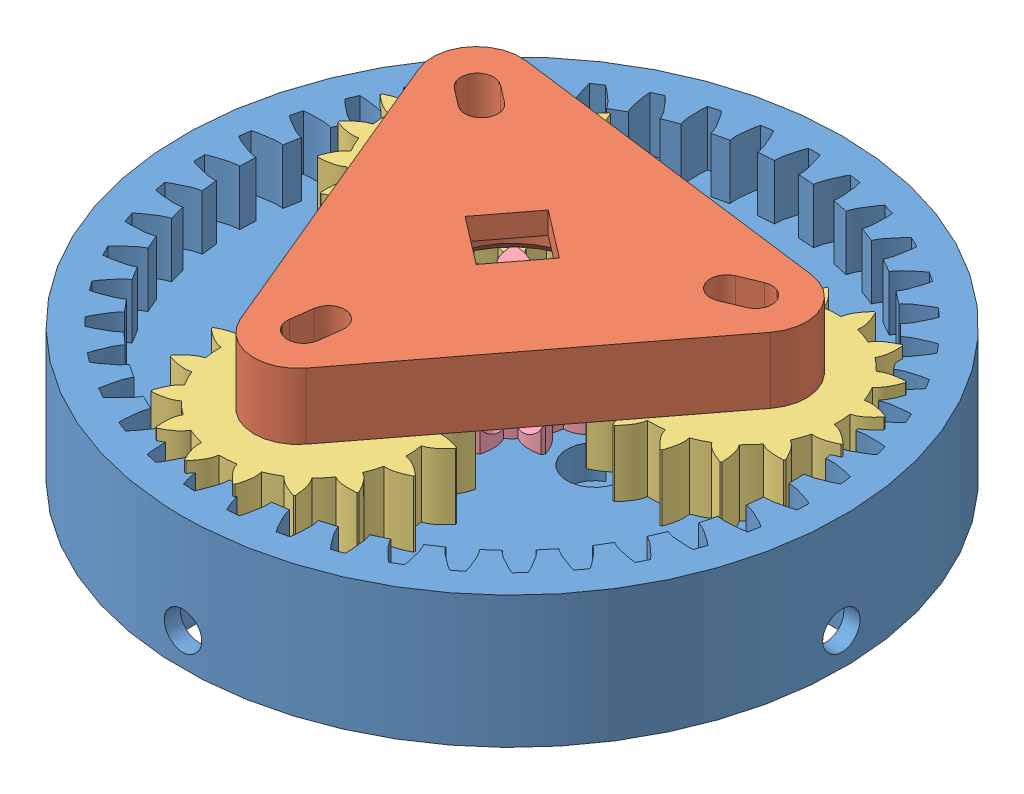
SolidWorks assembly Assem2, configuration Default. Lengths in mm.
Overall size (85.09 24.13 85.09).
7 component instances, 5 part files, 19 mates.
Components (placement in the parent):
- Planetary Gear Box 2.0, RING-1: Planetary Gear Box 2.0, RING [Default] at origin size (85.09 15.24 85.09)
- Planetary Gear Box 2.0, Coupling-1: Planetary Gear Box 2.0, Coupling [Default] at (0 12.7 0) x (0.607286 0 -0.794483) z (0.794483 0 0.607286) size (48.44 7.62 43.31)
- Planetary Gear Box 2.0, PLANETS-5: Planetary Gear Box 2.0, PLANETS [Default] at (-2.639 5.08 20.3375) x (-0.784541 0 0.620076) z (-0.620076 0 -0.784541) size (26.67 7.62 26.67)
- Planetary Gear Box 2.0, PLANETS-6: Planetary Gear Box 2.0, PLANETS [Default] at (-16.2933 5.08 -12.4542) x (-0.510108 0 0.86011) z (-0.86011 0 -0.510108) size (26.67 7.62 26.67)
- Planetary Gear Box 2.0, PLANETS-7: Planetary Gear Box 2.0, PLANETS [Default] at (18.9323 5.08 -7.8833) x (-0.509904 0 0.860231) z (-0.860231 0 -0.509904) size (26.67 7.62 26.67)
- Planetary Gear Box 2.0, SUN-1: Planetary Gear Box 2.0, SUN [Default] at (0 12.7 0) x (0.335275 0 0.94212) z (0.94212 0 -0.335275) size (18.98 7.62 18.72)
- Planetary Gear Box 2.0, SLEEVE-1: Planetary Gear Box 2.0, SLEEVE [Default] at (0 -3.937 0) size (85.34 36.83 85.34) (hidden)
Mates (geometry in assembly coordinates):
- Concentric1: concentric anti-aligned: cylinder of Planetary Gear Box 2.0, RING-1 through (0 -3.81 0) axis (0 1 0) radius 6.35; cylinder of Planetary Gear Box 2.0, Coupling-1 through (0 17.78 0) axis (0 -1 0) radius 8.128
- Slot1: slot anti-aligned: cylinder of Planetary Gear Box 2.0, PLANETS-5 through (-2.639 5.08 20.3375) axis (0 1 0) radius 1.905; plane of Planetary Gear Box 2.0, Coupling-1 through (-1.8892 20.32 -0.2451) normal (0.991686 0 0.128684); cylinder of Planetary Gear Box 2.0, Coupling-1 through (-2.4408 20.32 18.8096) axis (0 -1 0) radius 1.905
- Distance1: distance = 0 mm anti-aligned: plane of Planetary Gear Box 2.0, Coupling-1 through (0 12.7 0) normal (0 -1 0); plane of Planetary Gear Box 2.0, PLANETS-5 through (-2.639 12.7 20.3375) normal (0 1 0)
- Slot2: slot anti-aligned: cylinder of Planetary Gear Box 2.0, PLANETS-6 through (-16.2933 5.08 -12.4542) axis (0 1 0) radius 1.905; cylinder of Planetary Gear Box 2.0, Coupling-1 through (-17.0872 20.32 -13.0611) axis (0 -1 0) radius 1.905; cylinder of Planetary Gear Box 2.0, Coupling-1 through (-15.0692 20.32 -11.5186) axis (0 -1 0) radius 1.905
- Distance2: distance = 0 mm anti-aligned: plane of Planetary Gear Box 2.0, PLANETS-6 through (-16.2933 12.7 -12.4542) normal (0 1 0); plane of Planetary Gear Box 2.0, Coupling-1 through (0 12.7 0) normal (0 -1 0)
- Slot3: slot anti-aligned: cylinder of Planetary Gear Box 2.0, PLANETS-7 through (18.9323 5.08 -7.8833) axis (0 1 0) radius 1.905; cylinder of Planetary Gear Box 2.0, Coupling-1 through (17.51 20.32 -7.291) axis (0 -1 0) radius 1.905; cylinder of Planetary Gear Box 2.0, Coupling-1 through (19.8548 20.32 -8.2674) axis (0 -1 0) radius 1.905
- Distance3: distance = 0 mm anti-aligned: plane of Planetary Gear Box 2.0, PLANETS-7 through (18.9323 12.7 -7.8833) normal (0 1 0); plane of Planetary Gear Box 2.0, Coupling-1 through (0 12.7 0) normal (0 -1 0)
- Distance4: distance = 0 mm anti-aligned: plane of Planetary Gear Box 2.0, PLANETS-7 through (18.9323 5.08 -7.8833) normal (0 -1 0); plane of Planetary Gear Box 2.0, RING-1 through (0 5.08 0) normal (0 1 0)
- GearMate2: gear = 21.59 : 63.5 mm: circle of Planetary Gear Box 2.0, RING-1; circle of Planetary Gear Box 2.0, PLANETS-5
- GearMate3: gear = 63.5 : 21.59 mm: circle of Planetary Gear Box 2.0, PLANETS-7; circle of Planetary Gear Box 2.0, RING-1
- GearMate4: gear = 63.5 : 21.59 mm: circle of Planetary Gear Box 2.0, PLANETS-6; circle of Planetary Gear Box 2.0, RING-1
- Distance5: distance = 0 mm anti-aligned: plane of Planetary Gear Box 2.0, SUN-1 through (0 5.08 0) normal (0 -1 0); plane of Planetary Gear Box 2.0, RING-1 through (0 5.08 0) normal (0 1 0)
- Concentric2: concentric anti-aligned: cylinder of Planetary Gear Box 2.0, RING-1 through (0 -3.81 0) axis (0 1 0) radius 6.35; cylinder of Planetary Gear Box 2.0, SUN-1 through (0 12.7 0) axis (0 -1 0) radius 1.778
- GearMate5: gear = 21.59 : 13.97 mm: circle of Planetary Gear Box 2.0, SUN-1; circle of Planetary Gear Box 2.0, PLANETS-5
- Concentric3: concentric aligned: cylinder of Planetary Gear Box 2.0, RING-1 through (0 5.08 0) axis (0 -1 0) radius 38.1; cylinder of Planetary Gear Box 2.0, SLEEVE-1 through (0 25.273 0) axis (0 -1 0) radius 38.862
- Concentric4: concentric anti-aligned: cylinder of Planetary Gear Box 2.0, RING-1 through (0 0 38.101) axis (0 0 -1) radius 2.159; cylinder of Planetary Gear Box 2.0, SLEEVE-1 through (0 0 -42.672) axis (0 0 1) radius 2.159
- Distance6: distance = 22.352 mm: point of Planetary Gear Box 2.0, PLANETS-5; point of Planetary Gear Box 2.0, RING-1
- Distance7: distance = 22.352 mm: point of Planetary Gear Box 2.0, PLANETS-6; point of Planetary Gear Box 2.0, RING-1
- Distance8: distance = 22.352 mm: point of Planetary Gear Box 2.0, PLANETS-7; point of Planetary Gear Box 2.0, RING-1
